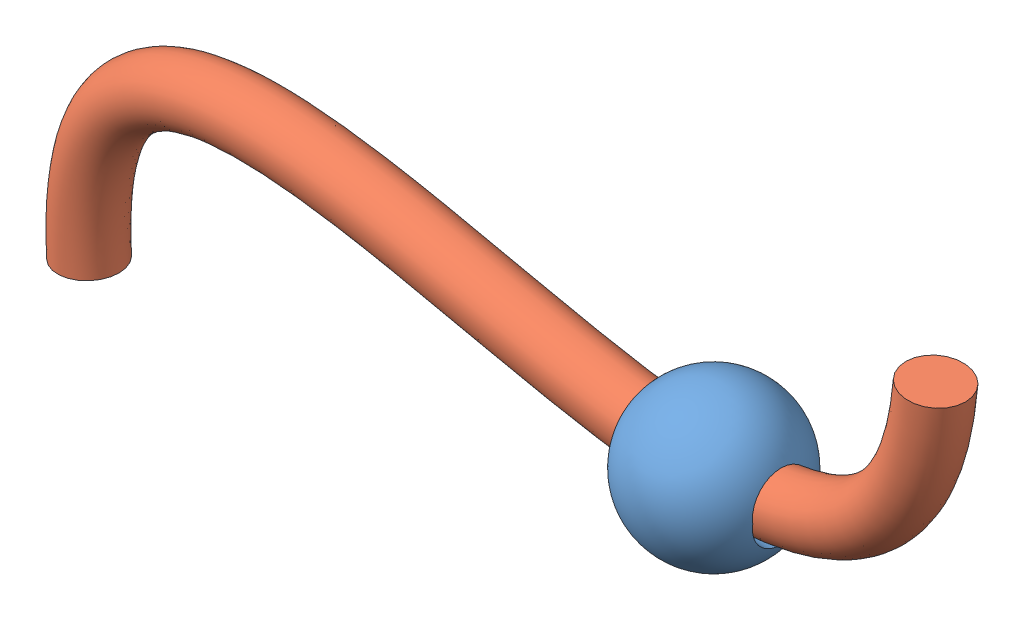
SolidWorks assembly Path Mate assembly, configuration Default. Lengths in mm.
Overall size (181.53 63.98 34.08).
2 component instances, 2 part files, 1 mates.
Components (placement in the parent):
- Ball-1: Ball [Default] at (-28.6889 57.7183 88.5267) x (-0.037734 -0.988455 -0.146741) z (-0.005598 -0.146634 0.989175) size (30 30 30)
- Path Mate-1: Path Mate [Default] at (-74.1159 64.4124 88.5267) size (181.53 63.98 12)
Mates (geometry in assembly coordinates):
- PathMate1: path = 65.9556 mm: point of Ball-1; curve of Path Mate-1
